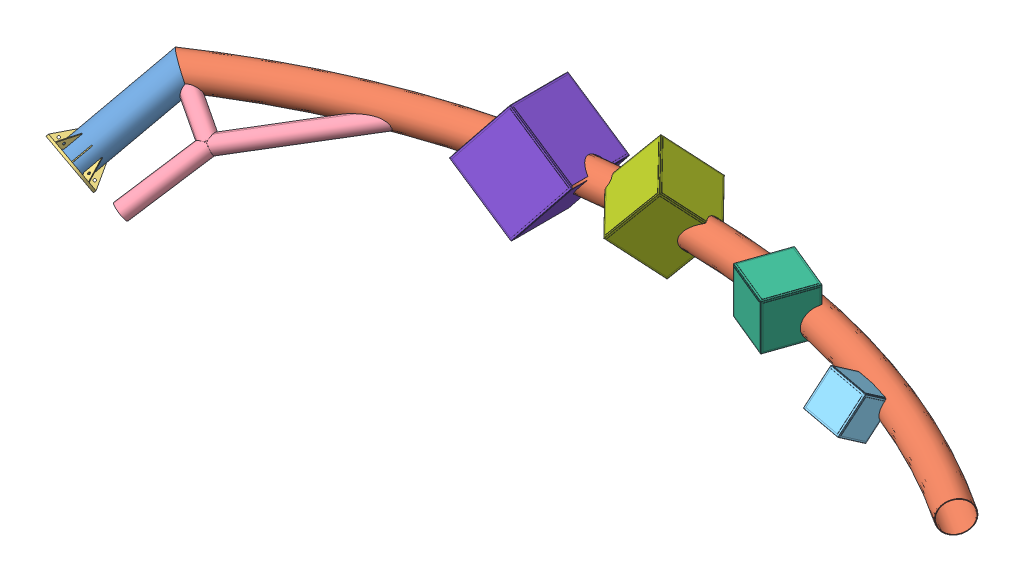
SolidWorks assembly tube1A with dimensions, configuration Default. Lengths in mm.
Overall size (5509.57 765.63 3983.87).
13 component instances, 12 part files, 24 mates.
Components (placement in the parent):
- tube1^tube1A with dimensions-1: tube1^tube1A with dimensions [A] at origin size (5509.57 567.54 3868.09) (virtual)
  - short-tube^tube1_tube1A with dimensions-1: short-tube^tube1_tube1A with dimensions [Default<As Machined>] at (-2066.9857 0 -335.3072) x (0.280011 0.524542 -0.804021) z (0.396988 0.699289 0.594471) size (592.32 168.28 168.28) (virtual)
  - tubes-1: tubes [tube1A] at origin size (5509.57 179.56 3868.09)
  - pipe_flange-1: pipe_flange [Default] at (-2222.5526 -291.4219 111.3861) x (0.228255 0.777129 0.58649) z (0.280011 0.524542 -0.804021) size (279.4 279.4 111.05)
-  tube1-support-arm^tube1A with dimensions-1:  tube1-support-arm^tube1A with dimensions [Default] at (-1841.3383 3296.5765 733.9451) x (0.486192 -0.007064 0.873823) z (0.120148 -0.98993 -0.074853) size (412.01 1066.18 424.01) (virtual)
- cube_positions-1: cube_positions [Default] at (-1823.1764 -3408.8204 760.8644) x (0.483946 0.016768 0.874937) z (-0.868168 0.134776 0.477619) size (10173.18 3894.08 5705.72) (hidden)
- cube_21-2: cube_21 [Default] at (1288.2494 29.6746 -537.6975) x (0.984604 -0.16863 0.046022) z (-0.163622 -0.79651 0.582065) size (201.3 201.3 201.3)
- cube_22-2: cube_22 [Default] at (645.1566 57.3606 -803.1505) x (0.933595 -0.053544 0.354308) z (-0.041789 -0.998295 -0.040754) size (257.18 257.18 257.18)
- cube_23-2: cube_23 [Default] at (-109.9957 38.0914 -951.4494) x (0.687918 -0.154019 0.709258) z (-0.466636 0.654617 0.59475) size (324.08 323.21 324.08)
- cube_24-2: cube_24 [Default] at (-714.1695 -0.9056 -890.2015) x (0.799244 -0.59975 -0.038856) z (0.182734 0.180907 0.966375) size (396.88 396.88 396.88)
- cube_25-2: cube_25 [Default] at (-1264.0995 -87.1885 -891.7679) x (0.987297 0.085082 -0.134183) z (0.001435 0.839726 0.543009) size (473.08 473.08 473.08) (hidden)
- cube_26-2: cube_26 [Default] at (-1666.8002 -83.8837 -624.8044) x (0.64678 -0.746775 0.15493) z (0.176738 0.344365 0.92205) size (549.27 549.27 549.27) (hidden)
- cube_27-2: cube_27 [Default] at (-1978.9147 -133.1093 -276.4109) x (0.852088 -0.443054 0.278657) z (0.115039 0.677912 0.726086) size (622.94 622.94 622.94) (hidden)
Mates (geometry in assembly coordinates):
- Coincident2: coincident aligned: plane of cube_positions-1 through (1370.7785 158.6976 -504.0275) normal (0.061496 0.580634 0.811839); plane of ? through (1368.4319 149.9369 -497.584) normal (0.061496 0.580634 0.811839)
- Coincident3: coincident aligned: plane of cube_positions-1 through (1151.7897 38.9489 -401.7939) normal (-0.984604 0.16863 -0.046022); plane of ? through (1180.494 175.5551 -515.3582) normal (-0.984604 0.16863 -0.046022)
- Coincident4: coincident aligned: plane of cube_positions-1 through (1359.0499 47.9597 -658.8607) normal (0.163622 0.79651 -0.582065); plane of ? through (1358.5546 48.3617 -658.4497) normal (0.163622 0.79651 -0.582065)
- Coincident5: coincident aligned: plane of cube_positions-1 through (-269.8545 257.6929 -1008.6691) normal (0.328364 0.842535 -0.42698); plane of ? through (138.0696 90.0062 -1025.8462) normal (0.328364 0.842535 -0.42698)
- Coincident6: coincident aligned: plane of cube_positions-1 through (-269.8545 257.6929 -1008.6691) normal (-0.515621 0.53864 0.666335); plane of ? through (-26.5058 248.7543 -813.1365) normal (-0.515621 0.53864 0.666335)
- Coincident7: coincident aligned: plane of cube_positions-1 through (-111.3669 92.1298 -1213.4822) normal (-0.791399 -0.001359 -0.611298); plane of ? through (-112.577 80.2194 -1211.8892) normal (-0.791399 -0.001359 -0.611298)
- Coincident8: coincident aligned: plane of cube_positions-1 through (427.5881 200.4324 -894.3456) normal (-0.273886 0.770862 0.575116); plane of ? through (664.3185 259.9517 -861.3851) normal (-0.273886 0.770862 0.575116)
- Coincident9: coincident aligned: plane of cube_positions-1 through (513.874 -129.2249 -836.3817) normal (-0.9585 -0.267985 -0.097269); plane of ? through (431.5111 185.4444 -891.7103) normal (-0.9585 -0.267985 -0.097269)
- Coincident10: coincident aligned: plane of cube_positions-1 through (494.5305 12.021 -1034.9137) normal (-0.079142 0.57789 -0.812268); plane of ? through (730.8323 76.6934 -1011.926) normal (-0.079142 0.57789 -0.812268)
- Coincident12: coincident aligned: plane of cube_positions-1 through (-791.9169 240.3471 -1106.1989) normal (0.572554 0.77947 -0.254183); plane of ? through (-485.0655 7.5339 -1128.946) normal (0.572554 0.77947 -0.254183)
- Coincident13: coincident aligned: plane of cube_positions-1 through (-1008.1904 -54.0858 -1010.1851) normal (-0.799244 0.59975 0.038856); plane of ? through (-799.7463 230.233 -1111.132) normal (-0.799244 0.59975 0.038856)
- Coincident14: coincident aligned: plane of cube_positions-1 through (-722.892 308.682 -741.1653) normal (0.182734 0.180907 0.966375); plane of ? through (-420.9363 68.6592 -753.33) normal (0.182734 0.180907 0.966375)
- Coincident15: coincident aligned: plane of cube_positions-1 through (-1552.1247 233.1481 -943.525) normal (-0.158877 0.536304 -0.828937); plane of ? through (-1096.6932 -115.469 -1256.362) normal (-0.158877 0.536304 -0.828937)
- Coincident16: coincident aligned: plane of cube_positions-1 through (-1480.6382 -8.1611 -570.5457) normal (-0.987297 -0.085082 0.134183); plane of ? through (-1551.0221 -160.7334 -1185.1631) normal (-0.987297 -0.085082 0.134183)
- Coincident17: coincident aligned: plane of cube_positions-1 through (-1036.4049 30.1216 -630.921) normal (0.001435 0.839726 0.543009); plane of ? through (-1094.2649 266.4932 -996.3008) normal (0.001435 0.839726 0.543009)
- Coincident18: coincident aligned: plane of cube_positions-1 through (-1767.5035 143.8571 -1007.8935) normal (0.741916 0.568981 -0.354712); plane of ? through (-1421.9314 -262.9012 -937.5613) normal (0.741916 0.568981 -0.354712)
- Coincident19: coincident aligned: plane of cube_positions-1 through (-2156.2784 -154.2974 -822.0193) normal (-0.64678 0.746775 -0.15493); plane of ? through (-1778.2485 132.6623 -1016.9969) normal (-0.64678 0.746775 -0.15493)
- Coincident20: coincident aligned: plane of cube_positions-1 through (-1674.8903 324.3095 -524.7258) normal (0.176738 0.344365 0.92205); plane of ? through (-1335.0623 -83.8996 -437.4068) normal (0.176738 0.344365 0.92205)
- Coincident21: coincident aligned: plane of cube_positions-1 through (-1649.3597 60.3279 -126.396) normal (0.510601 0.586633 -0.628609); plane of ? through (-1704.8777 -362.1635 -565.7704) normal (0.510601 0.586633 -0.628609)
- Coincident22: coincident aligned: plane of cube_positions-1 through (-2459.3101 -25.0118 81.6073) normal (-0.852088 0.443054 -0.278657); plane of ? through (-2231.8781 -97.6119 -729.2737) normal (-0.852088 0.443054 -0.278657)
- Coincident23: coincident aligned: plane of cube_positions-1 through (-1952.8489 -288.353 247.2347) normal (0.115039 0.677912 0.726086); plane of ? through (-1640.1686 46.0796 -114.5492) normal (0.115039 0.677912 0.726086)
- PLANE1: unknown = 871.22 mm: point of  tube1-support-arm^tube1A with dimensions-1; line of  tube1-support-arm^tube1A with dimensions-1 through (-1398.3111 1.0472 -597.9764) axis (-0.723666 -0.201431 0.660101); face of  tube1-support-arm^tube1A with dimensions-1
- Sketch6: unknown = 3721.9344 mm: unknown of cube_21-2; unknown of cube_21-2; unknown of cube_21-2; unknown of cube_21-2; unknown of cube_22-2; unknown of cube_22-2; unknown of cube_22-2; unknown of cube_23-2; unknown of cube_23-2; unknown of cube_23-2; unknown of cube_24-2; unknown of cube_24-2; unknown of cube_24-2; unknown of cube_24-2; unknown of tube1^tube1A with dimensions-1/tubes-1; unknown of tube1^tube1A with dimensions-1/short-tube^tube1_tube1A with dimensions-1
- Sketch7: unknown: unknown of cube_24-2; unknown of cube_23-2; unknown of cube_23-2; unknown of cube_22-2; unknown of cube_22-2; unknown of cube_21-2; unknown of cube_21-2; unknown of tube1^tube1A with dimensions-1/tubes-1; unknown of tube1^tube1A with dimensions-1/tubes-1; unknown of cube_24-2; plane of tube1^tube1A with dimensions-1/tubes-1 through (0 -84.1375 0) normal (0 1 0)
